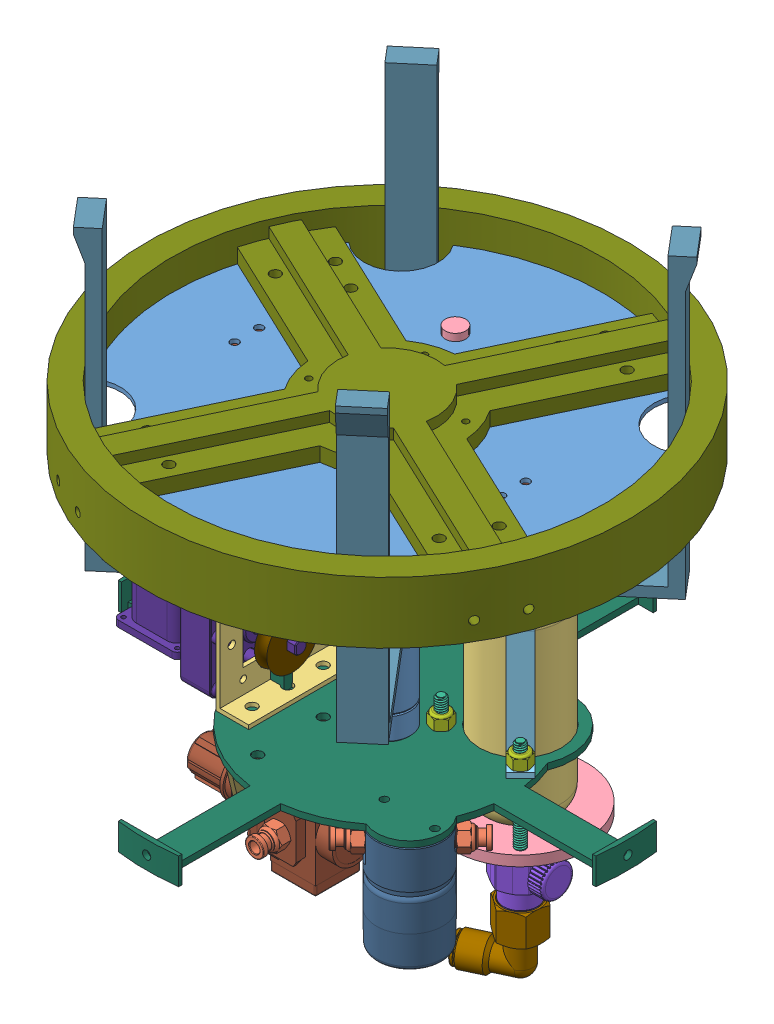
SolidWorks assembly 10004-R04_RECOVERY_SYSTEM, configuration Default. Lengths in mm.
Overall size (386.61 403.35 386.61).
42 component instances, 28 part files, 93 mates.
Components (placement in the parent):
- 6498K062_ROUND BODY AIR CYLINDER-2: 6498K062_ROUND BODY AIR CYLINDER [6498K062] at (101.6 47.752 101.6) x (0 -1 0) z (-0.809092 0 -0.587682) size (127.62 28.45 28.45)
- 16002-R01_BRASS_PUSH_TO_CONNECT_TUBE_FITTING_FOR_AIR (1)-1: 16002-R01_BRASS_PUSH_TO_CONNECT_TUBE_FITTING_FOR_AIR (1) [51025K177] at (86.3697 13.462 90.5375) x (-0.809092 0 -0.587682) z (-0.508948 -0.5 0.700694) size (22.87 14.66 12.7)
- 14019-R01_RECOVERY_PRESSURE_TANK (1)-1: 14019-R01_RECOVERY_PRESSURE_TANK (1) [Default] at (142.875 76.454 60.325) x (0.521453 0 0.85328) z (0.85328 0 -0.521453) size (50 133 50)
- 14020-R01_RECOVERY_PRESSURE_TANK_BULKHEAD (1)-7: 14020-R01_RECOVERY_PRESSURE_TANK_BULKHEAD (1) [Default] at (142.875 -41.1336 60.325) x (-0.707107 0 -0.707107) z (0.707107 0 -0.707107) size (82.15 6.35 82.15)
- 14021-R01_RECOVERY_PRESSURE_TANK__MOUNT-1: 14021-R01_RECOVERY_PRESSURE_TANK__MOUNT [Default] at (167.4293 6.35 84.8793) x (0.707107 0 0.707107) z (-0.707107 0 0.707107) size (82.15 73.28 12.7)
- 16005-R01_THREADED ROD-1: 16005-R01_THREADED ROD [98750A021] at (167.4293 -9.3836 84.8793) x (0 1 0) z (0 0 1) size (64.96 6.43 6.7)
- 16005-R01_THREADED ROD-2: 16005-R01_THREADED ROD [98750A021] at (118.3207 -9.3836 35.7707) x (0 1 0) z (0 0 1) size (64.96 6.43 6.7)
- 16005-R01_THREADED ROD-3: 16005-R01_THREADED ROD [98750A021] at (118.3207 -9.3836 84.8793) x (0 1 0) z (0 0 1) size (64.96 6.43 6.7)
- 16006-R01_NYLON-INSERT_NUTLOCK-1: 16006-R01_NYLON-INSERT_NUTLOCK [97135A210] at (167.4293 9.525 84.8793) x (0.707107 0 0.707107) z (-0.707107 0 0.707107) size (11.11 8.13 12.83)
- 16006-R01_NYLON-INSERT_NUTLOCK-2: 16006-R01_NYLON-INSERT_NUTLOCK [97135A210] at (118.3207 6.35 84.8793) x (0.965926 0 -0.258819) z (0.258819 0 0.965926) size (11.11 8.13 12.83)
- 16006-R01_NYLON-INSERT_NUTLOCK-3: 16006-R01_NYLON-INSERT_NUTLOCK [97135A210] at (118.3207 9.525 35.7707) x (0.965926 0 -0.258819) z (0.258819 0 0.965926) size (11.11 8.13 12.83)
- 16010-R01_ON_OFF_VALVE_FOR_RECOVERY_PRESSURE_TANK-1: 16010-R01_ON_OFF_VALVE_FOR_RECOVERY_PRESSURE_TANK [Default] at (142.875 -56.546 60.325) size (40 51.5 30.85)
- 16009-R01_PUSH_TO_CONNECT_TUBE_FITTING_FOR_AIR_90_DEGREE_SWIVEL-1: 16009-R01_PUSH_TO_CONNECT_TUBE_FITTING_FOR_AIR_90_DEGREE_SWIVEL [5225K893] at (142.875 -86.546 60.325) x (0.422618 0 0.906308) z (0 1 0) size (24.39 44.36 43.87)
- 16002-R01_BRASS_PUSH_TO_CONNECT_TUBE_FITTING_FOR_AIR (1)-5: 16002-R01_BRASS_PUSH_TO_CONNECT_TUBE_FITTING_FOR_AIR (1) [51025K177] at (91.275 -29.083 162.3949) x (0 0 1) z (0 -1 0) size (22.87 14.66 12.7)
- 16002-R01_BRASS_PUSH_TO_CONNECT_TUBE_FITTING_FOR_AIR (1)-7: 16002-R01_BRASS_PUSH_TO_CONNECT_TUBE_FITTING_FOR_AIR (1) [51025K177] at (91.275 -29.083 113.1951) x (0 0 -1) z (0.866025 0.5 0) size (22.87 14.66 12.7)
- 16003-R01_SURE-SEAL_STAINLESS STEEL_SOLENOID_VALVE (1)-3: 16003-R01_SURE-SEAL_STAINLESS STEEL_SOLENOID_VALVE (1) [4639K743] at (156.6334 -6.1976 142.7687) x (-0.706999 0 -0.707214) z (-0.707214 0 0.706999) size (69.98 72.57 41.1)
- 16004-R01_AIR_REGULATOR _WITH_BUILT-IN_PRESSURE_GAUGE (1)-3: 16004-R01_AIR_REGULATOR _WITH_BUILT-IN_PRESSURE_GAUGE (1) [8812K51] at (91.275 -29.083 137.795) x (0 0 -1) z (0 -1 0) size (40.79 94 58.3)
- 14022-R01_BRACKET_FOR_AIR_REGULATOR-1: 14022-R01_BRACKET_FOR_AIR_REGULATOR [Default] at (63.5 -29.083 137.795) x (0 -1 0) z (0 0 1) size (50.93 28.57 53.34)
- 16002-R01_BRASS_PUSH_TO_CONNECT_TUBE_FITTING_FOR_AIR (1)-9: 16002-R01_BRASS_PUSH_TO_CONNECT_TUBE_FITTING_FOR_AIR (1) [51025K177] at (174.4053 -6.1976 125.0022) x (0.707214 0 -0.706999) z (0.612279 0.5 0.612466) size (22.87 14.66 12.7)
- 16002-R01_BRASS_PUSH_TO_CONNECT_TUBE_FITTING_FOR_AIR (1)-10: 16002-R01_BRASS_PUSH_TO_CONNECT_TUBE_FITTING_FOR_AIR (1) [51025K177] at (139.6518 -6.1976 159.7451) x (-0.707214 0 0.706999) z (-0.612279 0.5 -0.612466) size (22.87 14.66 12.7)
- 16008-R01_PUSH_TO_CONNECT_TUBE_FITTING_FOR_AIR_STRAIGHT_ADAPTER-2: 16008-R01_PUSH_TO_CONNECT_TUBE_FITTING_FOR_AIR_STRAIGHT_ADAPTER [5779K719] at (92.2124 -79.6146 83.9494) x (-0.906308 0 0.422618) z (0 -1 0) size (16 16 50.04)
- Tube_4-10004-R01_Recovery_System (4)-1: Tube_4-10004-R01_Recovery_System (4) [Default] at origin size (71.08 37.36 56.07)
  - straight fitting-1: straight fitting [.25 TUBE X .25 NPT] at (148.1269 -6.1976 151.2726) x (0.707214 0 -0.706999) z (0.706999 0 0.707214) size (37.85 16.5 14.29) (hidden)
  - Tube-250X020^Tube_4-10004-R01_Recovery_System (4)-1: Tube-250X020^Tube_4-10004-R01_Recovery_System (4) [Tube .250in OD X .020in Wall] at (132.1396 -6.1976 167.255) x (0.577233 0.577409 0.577409) z (-0.707214 0 0.706999) size (39.07 13.45 39.63) (hidden, virtual)
- Tube_5-10004-R01_Recovery_System (4)-1: Tube_5-10004-R01_Recovery_System (4) [Default] at origin size (54.15 57.91 51.01)
  - straight fitting-1: straight fitting [.25 TUBE X .25 NPT] at (91.275 -29.083 131.7828) x (0 0 1) z (-1 0 0) size (37.85 16.5 14.29) (hidden)
  - Tube-250X020^Tube_5-10004-R01_Recovery_System (4)-1: Tube-250X020^Tube_5-10004-R01_Recovery_System (4) [Tube .250in OD X .020in Wall] at (91.275 -29.083 109.1768) x (0.707107 0.707107 0) z (0 0 -1) size (37.62 38.95 28.4) (hidden, virtual)
- Tube_7-10004-R01_Recovery_System (4)-1: Tube_7-10004-R01_Recovery_System (4) [Default] at origin size (179.67 88.63 166.88)
  - straight fitting-1: straight fitting [.25 TUBE X .25 NPT] at (97.0152 13.462 98.2699) x (0.809092 0 0.587682) z (-0.587682 0 0.809092) size (37.85 16.5 14.29) (hidden)
  - Tube-250X020^Tube_7-10004-R01_Recovery_System (4)-1: Tube-250X020^Tube_7-10004-R01_Recovery_System (4) [Tube .250in OD X .020in Wall] at (78.7249 13.462 84.9847) x (-0.456869 0.628995 0.628995) z (-0.809092 0 -0.587682) size (87.39 43.3 152.94) (hidden, virtual)
- Tube_11-10004-R01_Recovery_System (4)-005-1: Tube_11-10004-R01_Recovery_System (4)-005 [Default] at origin size (9.06 0 4.23) (hidden)
  - Tube-500X010_3^Tube_11-10004-R01_Recovery_System (4)-005-1: Tube-500X010_3^Tube_11-10004-R01_Recovery_System (4)-005 [Tube .500in OD X .010in Wall] at (124.2957 -120.546 68.9887) x (0.313146 0.671543 0.671543) z (-0.906308 0 0.422618) size (40.26 42.84 41.75) (hidden, virtual)
- 14018-R02_RECOVERY_SYSTEM_PLATE-1: 14018-R02_RECOVERY_SYSTEM_PLATE [Default] at (101.6 89.154 101.6) x (0.763342 0 -0.645995) z (0.645995 0 0.763342) size (274.32 184.15 274.32)
- 14022-R02_RECOVERY_SYSTEM_PISTON_MOUNT-1: 14022-R02_RECOVERY_SYSTEM_PISTON_MOUNT [Default] at (101.6 2.54 101.6) x (0 0 -1) z (1 0 0) size (298.45 83.83 298.45)
- 14011-R05_RECOVERY_MOUNTING_PLATE-1: 14011-R05_RECOVERY_MOUNTING_PLATE [Default<As Machined>] at (101.6 171.704 101.6) x (-0.941677 0 0.336517) z (-0.336517 0 -0.941677) size (298.45 38.1 298.45)
- 6142K430_COMPACT AC GEARMOTOR-1: 6142K430_COMPACT AC GEARMOTOR [6142K43] at (34.3773 39.37 105.4393) x (0 1 0) z (0.999999 0 -0.00118) size (66.04 78.99 104.65)
- 14025-R01-REDUNCDANCY_MOTOR_WHEEL-2: 14025-R01-REDUNCDANCY_MOTOR_WHEEL [Default] at (57.6358 39.37 120.2708) x (-0.999999 0 0.00118) z (0 1 0) size (7.62 31.75 31.75)
- 14034-R01_COVER_PLATE-1: 14034-R01_COVER_PLATE [Default] at (101.6 169.164 101.6) x (0.995996 0 -0.089398) z (0.089398 0 0.995996) size (266.7 2.54 266.7)
- 14032-R01_REDUNDANCY_PULLEY-1: 14032-R01_REDUNDANCY_PULLEY [Default] at (71.4819 138.684 101.3158) x (0.00118 0 0.999999) z (-0.999999 0 0.00118) size (30.48 53.34 203.2)
- 14033-R01_MOTOR_MOUNT-1: 14033-R01_MOTOR_MOUNT [Default] at (41.1083 39.37 105.4313) x (0 1 0) z (0.999999 0 -0.00118) size (66.08 88.22 20.32)
- 14042-R01_CHUTE_RELEASE_ACTUATOR-1: 14042-R01_CHUTE_RELEASE_ACTUATOR [Default] at (78.0943 157.099 35.8238) x (-0.941677 0 0.336517) z (0.336517 0 0.941677) size (63.97 69.85 47.72)
- 14043-R01_CHUTE_RELEASE_MOUNT-1: 14043-R01_CHUTE_RELEASE_MOUNT [Default] at (12.9556 166.624 42.2435) x (0.941677 0 -0.336517) z (0 -1 0) size (127 31.75 9.53)
Mates (geometry in assembly coordinates):
- Concentric3: concentric: cone of 6498K062_ROUND BODY AIR CYLINDER-2 through (91.0411 13.462 93.9306) axis (0.809092 0 0.587682); cylinder of 16002-R01_BRASS_PUSH_TO_CONNECT_TUBE_FITTING_FOR_AIR (1)-1 through (86.3697 13.462 90.5375) axis (0.809092 0 0.587682) radius 3.175
- Tangent1: tangent: cylinder of 6498K062_ROUND BODY AIR CYLINDER-2 through (101.6 76.454 101.6) axis (0 1 0) radius 14.224; plane of 16002-R01_BRASS_PUSH_TO_CONNECT_TUBE_FITTING_FOR_AIR (1)-1 through (94.4006 13.462 87.3083) normal (0.809092 0 0.587682)
- Coincident12: coincident: plane of 6498K062_ROUND BODY AIR CYLINDER-2 through (109.9592 76.454 90.0915) normal (0 1 0); plane of 14019-R01_RECOVERY_PRESSURE_TANK (1)-1 through (142.875 76.454 60.325) normal (0 1 0)
- Concentric53: concentric: circle of 14019-R01_RECOVERY_PRESSURE_TANK (1)-1; circle of 14020-R01_RECOVERY_PRESSURE_TANK_BULKHEAD (1)-7
- Concentric54: concentric: cylinder of 14019-R01_RECOVERY_PRESSURE_TANK (1)-1 through (142.875 -56.546 60.325) axis (0 -1 0) radius 25; cylinder of 14020-R01_RECOVERY_PRESSURE_TANK_BULKHEAD (1)-7 through (142.875 -34.7836 60.325) axis (0 -1 0) radius 18.796
- Tangent15: tangent: torus of 14019-R01_RECOVERY_PRESSURE_TANK (1)-1; circle of 14020-R01_RECOVERY_PRESSURE_TANK_BULKHEAD (1)-7
- Concentric69: concentric: cylinder of 14020-R01_RECOVERY_PRESSURE_TANK_BULKHEAD (1)-7 through (167.4293 -34.7836 84.8793) axis (0 -1 0) radius 3.175; circle of 16005-R01_THREADED ROD-1
- Coincident47: coincident: plane of 14020-R01_RECOVERY_PRESSURE_TANK_BULKHEAD (1)-7 through (142.875 -41.1336 60.325) normal (0 -1 0); plane of 16005-R01_THREADED ROD-1 through (167.4293 -41.1336 84.8793) normal (0 -1 0)
- Concentric70: concentric: cylinder of 14020-R01_RECOVERY_PRESSURE_TANK_BULKHEAD (1)-7 through (118.3207 -34.7836 35.7707) axis (0 -1 0) radius 3.175; circle of 16005-R01_THREADED ROD-2
- Coincident48: coincident: plane of 14020-R01_RECOVERY_PRESSURE_TANK_BULKHEAD (1)-7 through (142.875 -41.1336 60.325) normal (0 -1 0); plane of 16005-R01_THREADED ROD-2 through (118.3207 -41.1336 35.7707) normal (0 -1 0)
- Concentric71: concentric: cylinder of 14020-R01_RECOVERY_PRESSURE_TANK_BULKHEAD (1)-7 through (118.3207 -34.7836 84.8793) axis (0 -1 0) radius 3.175; circle of 16005-R01_THREADED ROD-3
- Coincident49: coincident: plane of 14020-R01_RECOVERY_PRESSURE_TANK_BULKHEAD (1)-7 through (142.875 -41.1336 60.325) normal (0 -1 0); plane of 16005-R01_THREADED ROD-3 through (118.3207 -41.1336 84.8793) normal (0 -1 0)
- Coincident50: coincident: cylinder of 14020-R01_RECOVERY_PRESSURE_TANK_BULKHEAD (1)-7 through (167.4293 -34.7836 84.8793) axis (0 -1 0) radius 3.175; circle of 16006-R01_NYLON-INSERT_NUTLOCK-1
- Coincident51: coincident: plane of 14021-R01_RECOVERY_PRESSURE_TANK__MOUNT-1 through (167.4293 9.525 84.8793) normal (0 1 0); plane of 16006-R01_NYLON-INSERT_NUTLOCK-1 through (173.6265 9.525 86.5398) normal (0 -1 0)
- Parallel10: parallel: plane of 14021-R01_RECOVERY_PRESSURE_TANK__MOUNT-1 through (171.9194 9.525 89.3694) normal (0.707107 0 0.707107); plane of 16006-R01_NYLON-INSERT_NUTLOCK-1 through (169.0898 17.4625 91.0765) normal (0.707107 0 0.707107)
- Concentric72: concentric: circle of 16005-R01_THREADED ROD-2; circle of 16006-R01_NYLON-INSERT_NUTLOCK-3
- Coincident52: coincident: plane of 14021-R01_RECOVERY_PRESSURE_TANK__MOUNT-1 through (167.4293 9.525 84.8793) normal (0 1 0); plane of 16006-R01_NYLON-INSERT_NUTLOCK-3 through (122.8574 9.525 31.2341) normal (0 -1 0)
- Parallel11: parallel: plane of 14021-R01_RECOVERY_PRESSURE_TANK__MOUNT-1 through (113.8306 9.525 31.2806) normal (-0.707107 0 -0.707107); plane of 16006-R01_NYLON-INSERT_NUTLOCK-3 through (116.6602 17.4625 29.5735) normal (-0.707107 0 -0.707107)
- Concentric73: concentric: circle of 16005-R01_THREADED ROD-3; circle of 16006-R01_NYLON-INSERT_NUTLOCK-2
- Parallel12: parallel: plane of 14021-R01_RECOVERY_PRESSURE_TANK__MOUNT-1 through (113.8306 9.525 31.2806) normal (-0.707107 0 -0.707107); plane of 16006-R01_NYLON-INSERT_NUTLOCK-2 through (116.6602 14.2875 78.6821) normal (-0.707107 0 -0.707107)
- Concentric74: concentric: cylinder of 14019-R01_RECOVERY_PRESSURE_TANK (1)-1 through (142.875 -56.546 60.325) axis (0 -1 0) radius 9.325; cylinder of 16010-R01_ON_OFF_VALVE_FOR_RECOVERY_PRESSURE_TANK-1 through (142.875 -86.546 60.325) axis (0 1 0) radius 10.4775
- Coincident54: coincident: plane of 14019-R01_RECOVERY_PRESSURE_TANK (1)-1 through (142.875 -56.546 60.325) normal (0 -1 0); plane of 16010-R01_ON_OFF_VALVE_FOR_RECOVERY_PRESSURE_TANK-1 through (130.375 -56.546 67.5419) normal (0 1 0)
- Concentric76: concentric: cylinder of 16010-R01_ON_OFF_VALVE_FOR_RECOVERY_PRESSURE_TANK-1 through (142.875 -86.546 60.325) axis (0 1 0) radius 10.4775; circle of 16009-R01_PUSH_TO_CONNECT_TUBE_FITTING_FOR_AIR_90_DEGREE_SWIVEL-1
- Coincident57: coincident: plane of 16010-R01_ON_OFF_VALVE_FOR_RECOVERY_PRESSURE_TANK-1 through (142.875 -86.546 60.325) normal (0 -1 0); plane of 16009-R01_PUSH_TO_CONNECT_TUBE_FITTING_FOR_AIR_90_DEGREE_SWIVEL-1 through (142.875 -86.546 60.325) normal (0 1 0)
- Concentric87: concentric: cylinder of 16004-R01_AIR_REGULATOR _WITH_BUILT-IN_PRESSURE_GAUGE (1)-3 through (54.175 -29.083 137.795) axis (1 0 0) radius 14; cylinder of 14022-R01_BRACKET_FOR_AIR_REGULATOR-1 through (66.675 -29.083 137.795) axis (-1 0 0) radius 13.97
- Coincident62: coincident: plane of 16004-R01_AIR_REGULATOR _WITH_BUILT-IN_PRESSURE_GAUGE (1)-3 through (66.675 -12.333 153.0103) normal (-1 0 0); plane of 14022-R01_BRACKET_FOR_AIR_REGULATOR-1 through (66.675 -29.083 137.795) normal (1 0 0)
- Parallel16: parallel: plane of 16004-R01_AIR_REGULATOR _WITH_BUILT-IN_PRESSURE_GAUGE (1)-3 through (79.275 -0.583 151.795) normal (0 1 0); plane of 14022-R01_BRACKET_FOR_AIR_REGULATOR-1 through (92.075 -0.635 137.795) normal (0 -1 0)
- Concentric88: concentric: cylinder of 16002-R01_BRASS_PUSH_TO_CONNECT_TUBE_FITTING_FOR_AIR (1)-5 through (91.275 -29.083 162.3949) axis (0 0 -1) radius 2.3876; circle of 16004-R01_AIR_REGULATOR _WITH_BUILT-IN_PRESSURE_GAUGE (1)-3
- Coincident64: coincident: plane of 16002-R01_BRASS_PUSH_TO_CONNECT_TUBE_FITTING_FOR_AIR (1)-5 through (87.6088 -22.733 157.795) normal (0 0 -1); plane of 16004-R01_AIR_REGULATOR _WITH_BUILT-IN_PRESSURE_GAUGE (1)-3 through (99.4584 -43.083 157.795) normal (0 0 1)
- Parallel17: parallel: plane of 16002-R01_BRASS_PUSH_TO_CONNECT_TUBE_FITTING_FOR_AIR (1)-5 through (87.6088 -35.433 164.3665) normal (0 -1 0); plane of 16004-R01_AIR_REGULATOR _WITH_BUILT-IN_PRESSURE_GAUGE (1)-3 through (99.4584 -43.083 117.795) normal (0 -1 0)
- Concentric89: concentric: cylinder of 16002-R01_BRASS_PUSH_TO_CONNECT_TUBE_FITTING_FOR_AIR (1)-7 through (91.275 -29.083 113.1951) axis (0 0 1) radius 2.3876; circle of 16004-R01_AIR_REGULATOR _WITH_BUILT-IN_PRESSURE_GAUGE (1)-3
- Coincident66: coincident: plane of 16002-R01_BRASS_PUSH_TO_CONNECT_TUBE_FITTING_FOR_AIR (1)-7 through (83.9427 -29.083 117.795) normal (0 0 1); plane of 16004-R01_AIR_REGULATOR _WITH_BUILT-IN_PRESSURE_GAUGE (1)-3 through (99.4584 -43.083 117.795) normal (0 0 -1)
- Parallel18: parallel: plane of 16002-R01_BRASS_PUSH_TO_CONNECT_TUBE_FITTING_FOR_AIR (1)-7 through (94.9412 -35.433 111.2235) normal (0 -1 0); plane of 16004-R01_AIR_REGULATOR _WITH_BUILT-IN_PRESSURE_GAUGE (1)-3 through (99.4584 -43.083 117.795) normal (0 -1 0)
- Concentric95: concentric: circle of 16003-R01_SURE-SEAL_STAINLESS STEEL_SOLENOID_VALVE (1)-3; cylinder of 16002-R01_BRASS_PUSH_TO_CONNECT_TUBE_FITTING_FOR_AIR (1)-10 through (139.6518 -6.1976 159.7451) axis (0.707214 0 -0.706999) radius 3.175
- Coincident69: coincident: plane of 16003-R01_SURE-SEAL_STAINLESS STEEL_SOLENOID_VALVE (1)-3 through (147.6286 -16.1406 161.218) normal (-0.707214 0 0.706999); plane of 16002-R01_BRASS_PUSH_TO_CONNECT_TUBE_FITTING_FOR_AIR (1)-10 through (148.089 -6.1976 161.6785) normal (0.707214 0 -0.706999)
- Parallel20: parallel: plane of 16003-R01_SURE-SEAL_STAINLESS STEEL_SOLENOID_VALVE (1)-3 through (141.8268 -21.2598 127.9575) normal (0 -1 0); plane of 16002-R01_BRASS_PUSH_TO_CONNECT_TUBE_FITTING_FOR_AIR (1)-10 through (135.6656 -12.5476 158.5462) normal (0 -1 0)
- Concentric96: concentric: cylinder of 16002-R01_BRASS_PUSH_TO_CONNECT_TUBE_FITTING_FOR_AIR (1)-9 through (174.4053 -6.1976 125.0022) axis (-0.707214 0 0.706999) radius 3.175; cylinder of 16002-R01_BRASS_PUSH_TO_CONNECT_TUBE_FITTING_FOR_AIR (1)-10 through (139.6518 -6.1976 159.7451) axis (0.707214 0 -0.706999) radius 3.175
- Tangent16: tangent: cylinder of 16003-R01_SURE-SEAL_STAINLESS STEEL_SOLENOID_VALVE (1)-3 through (156.6334 -24.4348 142.7687) axis (0 1 0) radius 20.5296; plane of 16002-R01_BRASS_PUSH_TO_CONNECT_TUBE_FITTING_FOR_AIR (1)-9 through (165.9682 -6.1976 123.0688) normal (-0.707214 0 0.706999)
- Parallel21: parallel: plane of 16003-R01_SURE-SEAL_STAINLESS STEEL_SOLENOID_VALVE (1)-3 through (141.8268 -21.2598 127.9575) normal (0 -1 0); plane of 16002-R01_BRASS_PUSH_TO_CONNECT_TUBE_FITTING_FOR_AIR (1)-9 through (178.3916 -12.5476 126.2011) normal (0 -1 0)
- Distance2: distance = 63.5 mm: plane of 14020-R01_RECOVERY_PRESSURE_TANK_BULKHEAD (1)-7 through (142.875 -41.1336 60.325) normal (0 -1 0); plane of 16008-R01_PUSH_TO_CONNECT_TUBE_FITTING_FOR_AIR_STRAIGHT_ADAPTER-2 through (89.5288 -104.6336 78.1943) normal (0 -1 0)
- Distance3: distance = 25.4 mm: plane of 16008-R01_PUSH_TO_CONNECT_TUBE_FITTING_FOR_AIR_STRAIGHT_ADAPTER-2 through (92.2124 -79.6146 83.9494) normal (-0.906308 0 0.422618); plane of 16009-R01_PUSH_TO_CONNECT_TUBE_FITTING_FOR_AIR_90_DEGREE_SWIVEL-1 through (115.2326 -112.504 73.2149) normal (-0.906308 0 0.422618)
- Coincident77: coincident: plane of 16009-R01_PUSH_TO_CONNECT_TUBE_FITTING_FOR_AIR_90_DEGREE_SWIVEL-1 through (142.875 -86.546 60.325) normal (0.422618 0 0.906308); plane of 16008-R01_PUSH_TO_CONNECT_TUBE_FITTING_FOR_AIR_STRAIGHT_ADAPTER-2 through (92.2124 -79.6146 83.9494) normal (-0.422618 0 -0.906308)
- Angle1: planar angle = 0.174533 rad: plane of 16009-R01_PUSH_TO_CONNECT_TUBE_FITTING_FOR_AIR_90_DEGREE_SWIVEL-1 through (155.4332 -105.746 54.469) normal (0.573576 0 -0.819152); plane of 14021-R01_RECOVERY_PRESSURE_TANK__MOUNT-1 through (171.9194 9.525 80.3892) normal (0.707107 0 -0.707107)
- Concentric99: concentric: circle of 6498K062_ROUND BODY AIR CYLINDER-2; circle of 14022-R02_RECOVERY_SYSTEM_PISTON_MOUNT-1
- Coincident88: coincident: plane of 6498K062_ROUND BODY AIR CYLINDER-2 through (109.9592 6.35 90.0915) normal (0 -1 0); plane of 14022-R02_RECOVERY_SYSTEM_PISTON_MOUNT-1 through (101.6 6.35 101.6) normal (0 1 0)
- Parallel28: parallel: plane of 14022-R02_RECOVERY_SYSTEM_PISTON_MOUNT-1 through (111.125 6.35 111.125) normal (0 0 1); plane of assembly through (0 0 0) normal (0 0 1)
- Perpendicular1: perpendicular: plane of 14022-R02_RECOVERY_SYSTEM_PISTON_MOUNT-1 through (92.075 6.35 111.125) normal (-1 0 0); plane of assembly through (0 0 0) normal (0 0 1)
- Concentric101: concentric: circle of 6498K062_ROUND BODY AIR CYLINDER-2; circle of 14018-R02_RECOVERY_SYSTEM_PLATE-1
- Coincident91: coincident: plane of 6498K062_ROUND BODY AIR CYLINDER-2 through (101.6 89.154 101.6) normal (0 1 0); plane of 14018-R02_RECOVERY_SYSTEM_PLATE-1 through (101.6 89.154 101.6) normal (0 -1 0)
- Coincident92: coincident: plane of 16003-R01_SURE-SEAL_STAINLESS STEEL_SOLENOID_VALVE (1)-3 through (156.6334 2.54 142.7687) normal (0 1 0); plane of 14022-R02_RECOVERY_SYSTEM_PISTON_MOUNT-1 through (101.6 2.54 101.6) normal (0 -1 0)
- Concentric103: concentric: circle of 16003-R01_SURE-SEAL_STAINLESS STEEL_SOLENOID_VALVE (1)-3; circle of 14022-R02_RECOVERY_SYSTEM_PISTON_MOUNT-1
- Concentric104: concentric: circle of 16003-R01_SURE-SEAL_STAINLESS STEEL_SOLENOID_VALVE (1)-3; circle of 14022-R02_RECOVERY_SYSTEM_PISTON_MOUNT-1
- Coincident95: coincident: plane of 14021-R01_RECOVERY_PRESSURE_TANK__MOUNT-1 through (167.4293 6.35 84.8793) normal (0 -1 0); plane of 14022-R02_RECOVERY_SYSTEM_PISTON_MOUNT-1 through (101.6 6.35 101.6) normal (0 1 0)
- Parallel31: parallel: plane of 14021-R01_RECOVERY_PRESSURE_TANK__MOUNT-1 through (167.4293 6.35 84.8793) normal (0 -1 0); plane of 14022-R02_RECOVERY_SYSTEM_PISTON_MOUNT-1 through (101.6 2.54 101.6) normal (0 -1 0)
- Coincident97: coincident: plane of 14021-R01_RECOVERY_PRESSURE_TANK__MOUNT-1 through (167.4293 9.525 84.8793) normal (0 1 0); plane of 16006-R01_NYLON-INSERT_NUTLOCK-1 through (173.6265 9.525 86.5398) normal (0 -1 0)
- Concentric105: concentric: circle of 14019-R01_RECOVERY_PRESSURE_TANK (1)-1; circle of 14022-R02_RECOVERY_SYSTEM_PISTON_MOUNT-1
- Concentric106: concentric: circle of 16006-R01_NYLON-INSERT_NUTLOCK-2; circle of 14022-R02_RECOVERY_SYSTEM_PISTON_MOUNT-1
- Coincident100: coincident: plane of 16006-R01_NYLON-INSERT_NUTLOCK-2 through (122.8574 6.35 80.3426) normal (0 -1 0); plane of 14022-R02_RECOVERY_SYSTEM_PISTON_MOUNT-1 through (101.6 6.35 101.6) normal (0 1 0)
- Concentric107: concentric: circle of 14021-R01_RECOVERY_PRESSURE_TANK__MOUNT-1; circle of 14022-R02_RECOVERY_SYSTEM_PISTON_MOUNT-1
- Concentric108: concentric: circle of 14021-R01_RECOVERY_PRESSURE_TANK__MOUNT-1; circle of 14022-R02_RECOVERY_SYSTEM_PISTON_MOUNT-1
- Coincident105: coincident: plane of 14022-R01_BRACKET_FOR_AIR_REGULATOR-1 through (66.675 2.54 137.795) normal (0 1 0); plane of 14022-R02_RECOVERY_SYSTEM_PISTON_MOUNT-1 through (101.6 2.54 101.6) normal (0 -1 0)
- Concentric109: concentric: circle of 6498K062_ROUND BODY AIR CYLINDER-2; circle of 14011-R05_RECOVERY_MOUNTING_PLATE-1
- Concentric114: concentric: circle of 6142K430_COMPACT AC GEARMOTOR-1; circle of 14025-R01-REDUNCDANCY_MOTOR_WHEEL-2
- Parallel34: parallel: plane of 6142K430_COMPACT AC GEARMOTOR-1 through (53.8296 28.7481 123.4478) normal (0.00118 0 0.999999); plane of 14025-R01-REDUNCDANCY_MOTOR_WHEEL-2 through (61.4497 41.7392 123.5683) normal (-0.00118 0 -0.999999)
- Coincident113: coincident: plane of 6142K430_COMPACT AC GEARMOTOR-1 through (53.8296 28.7481 123.4478) normal (0.999999 0 -0.00118); plane of 14025-R01-REDUNCDANCY_MOTOR_WHEEL-2 through (53.8446 39.37 136.1503) normal (-0.999999 0 0.00118)
- Distance4: distance = 76.2 mm: plane of 14011-R05_RECOVERY_MOUNTING_PLATE-1 through (101.6 171.704 101.6) normal (0 -1 0); plane of 14018-R02_RECOVERY_SYSTEM_PLATE-1 through (101.6 95.504 101.6) normal (0 1 0)
- Coincident116: coincident: plane of 14011-R05_RECOVERY_MOUNTING_PLATE-1 through (101.6 171.704 101.6) normal (0 -1 0); plane of 14034-R01_COVER_PLATE-1 through (150.8515 171.704 56.6573) normal (0 1 0)
- Coincident120: coincident: plane of 14034-R01_COVER_PLATE-1 through (150.8515 169.164 56.6573) normal (0 -1 0); plane of 14032-R01_REDUNDANCY_PULLEY-1 through (84.1917 169.164 109.5558) normal (0 1 0)
- Concentric122: concentric: circle of 14011-R05_RECOVERY_MOUNTING_PLATE-1; circle of 14034-R01_COVER_PLATE-1
- Concentric123: concentric: circle of 14011-R05_RECOVERY_MOUNTING_PLATE-1; circle of 14034-R01_COVER_PLATE-1
- Concentric124: concentric: circle of 14011-R05_RECOVERY_MOUNTING_PLATE-1; circle of 14034-R01_COVER_PLATE-1
- Concentric125: concentric: circle of 14011-R05_RECOVERY_MOUNTING_PLATE-1; circle of 14034-R01_COVER_PLATE-1
- Coincident121: coincident: plane of 14022-R02_RECOVERY_SYSTEM_PISTON_MOUNT-1 through (101.6 6.35 101.6) normal (0 1 0); plane of 6142K430_COMPACT AC GEARMOTOR-1 through (15.8305 6.35 144.4502) normal (0 -1 0)
- Perpendicular2: perpendicular: line of 6142K430_COMPACT AC GEARMOTOR-1 through (34.3369 71.628 71.2128) axis (0.00118 0 0.999999); line of 14032-R01_REDUNDANCY_PULLEY-1 through (-4.7 167.386 116.6457) axis (0.999999 0 -0.00118)
- InPlace2: in place: plane of 6142K430_COMPACT AC GEARMOTOR-1 through (41.1258 39.37 120.2903) normal (0.999999 0 -0.00118); plane of ? through (40.9838 0 -0.0484) normal (0.999999 0 -0.00118); moOrthogonalPlaneRef_w of 6142K430_COMPACT AC GEARMOTOR-1 through (41.1258 39.37 120.2903) normal (0.999999 0 -0.00118); plane of ? through (40.9838 0 -0.0484) normal (0 1 0); plane of 6142K430_COMPACT AC GEARMOTOR-1 through (41.1258 39.37 120.2903) normal (0.999999 0 -0.00118); plane of ? through (40.9838 0 -0.0484) normal (-0.00118 0 -0.999999); plane of 6142K430_COMPACT AC GEARMOTOR-1 through (41.1258 39.37 120.2903) normal (0.999999 0 -0.00118); unknown of 14033-R01_MOTOR_MOUNT-1
- Coincident126: coincident: plane of 6142K430_COMPACT AC GEARMOTOR-1; plane of 14033-R01_MOTOR_MOUNT-1
- Coincident127: coincident: moOrthogonalPlaneRef_w of 6142K430_COMPACT AC GEARMOTOR-1 through (41.1083 39.37 105.4313) normal (0.00118 0 0.999999); plane of 14033-R01_MOTOR_MOUNT-1 through (41.1083 39.37 105.4313) normal (0.00118 0 0.999999)
- Coincident128: coincident: moOrthogonalPlaneRef_w of 6142K430_COMPACT AC GEARMOTOR-1 through (41.1083 39.37 105.4313) normal (0 -1 0); plane of 14033-R01_MOTOR_MOUNT-1 through (41.1083 39.37 105.4313) normal (0 1 0)
- Parallel36: parallel: plane of 14022-R02_RECOVERY_SYSTEM_PISTON_MOUNT-1 through (101.6 6.35 101.6) normal (0 1 0); plane of 14033-R01_MOTOR_MOUNT-1 through (43.6928 6.3288 143.1092) normal (0 -1 0)
- Concentric126: concentric: circle of 14022-R02_RECOVERY_SYSTEM_PISTON_MOUNT-1; circle of 14033-R01_MOTOR_MOUNT-1
- Concentric127: concentric: cylinder of 14022-R02_RECOVERY_SYSTEM_PISTON_MOUNT-1 through (52.4968 -11.43 70.2217) axis (0 1 0) radius 3.175; circle of 14033-R01_MOTOR_MOUNT-1
- Concentric128: concentric: circle of 6142K430_COMPACT AC GEARMOTOR-1; circle of 14033-R01_MOTOR_MOUNT-1
- Concentric129: concentric: circle of 6142K430_COMPACT AC GEARMOTOR-1; circle of 14033-R01_MOTOR_MOUNT-1
- Perpendicular3: perpendicular: line of 14032-R01_REDUNDANCY_PULLEY-1 through (58.167 167.386 109.5865) axis (0.999999 0 -0.00118); line of 14033-R01_MOTOR_MOUNT-1 through (43.5938 72.4112 59.2053) axis (0.00118 0 0.999999)
- Concentric130: concentric: circle of 14034-R01_COVER_PLATE-1; circle of 14032-R01_REDUNDANCY_PULLEY-1
- Concentric131: concentric: circle of 14034-R01_COVER_PLATE-1; circle of 14032-R01_REDUNDANCY_PULLEY-1
- Angle2: planar angle = 2.715304 rad: line of 14018-R02_RECOVERY_SYSTEM_PLATE-1 through (13.9782 95.504 190.7255) axis (0.763342 0 -0.645995); line of 14011-R05_RECOVERY_MOUNTING_PLATE-1 through (82.0843 186.944 125.013) axis (-0.427913 0 0.90382)
- Distance5: distance = 5.08 mm: plane of 14011-R05_RECOVERY_MOUNTING_PLATE-1 through (101.6 171.704 101.6) normal (0 -1 0); plane of 14043-R01_CHUTE_RELEASE_MOUNT-1 through (12.9556 166.624 42.2435) normal (0 1 0)
- Concentric132: concentric: cylinder of 14011-R05_RECOVERY_MOUNTING_PLATE-1 through (125.9315 152.653 18.7288) axis (0 1 0) radius 3.175; cylinder of 14043-R01_CHUTE_RELEASE_MOUNT-1 through (125.9315 166.624 18.7288) axis (0 -1 0) radius 3.175
- Concentric133: concentric: cylinder of 14011-R05_RECOVERY_MOUNTING_PLATE-1 through (30.2571 152.653 52.9189) axis (0 1 0) radius 3.175; cylinder of 14043-R01_CHUTE_RELEASE_MOUNT-1 through (30.2571 166.624 52.9189) axis (0 -1 0) radius 3.175
- Coincident123: coincident: plane of 14042-R01_CHUTE_RELEASE_ACTUATOR-1 through (78.0943 157.099 35.8238) normal (0 1 0); plane of 14043-R01_CHUTE_RELEASE_MOUNT-1 through (12.9556 157.099 42.2435) normal (0 -1 0)
- Concentric134: concentric: cylinder of 14042-R01_CHUTE_RELEASE_ACTUATOR-1 through (55.3716 150.749 43.944) axis (0 1 0) radius 3.175; cylinder of 14043-R01_CHUTE_RELEASE_MOUNT-1 through (55.3716 166.625 43.944) axis (0 -1 0) radius 3.175
- Concentric135: concentric: cylinder of 14042-R01_CHUTE_RELEASE_ACTUATOR-1 through (100.817 150.749 27.7037) axis (0 1 0) radius 3.175; cylinder of 14043-R01_CHUTE_RELEASE_MOUNT-1 through (100.817 166.625 27.7037) axis (0 -1 0) radius 3.175
